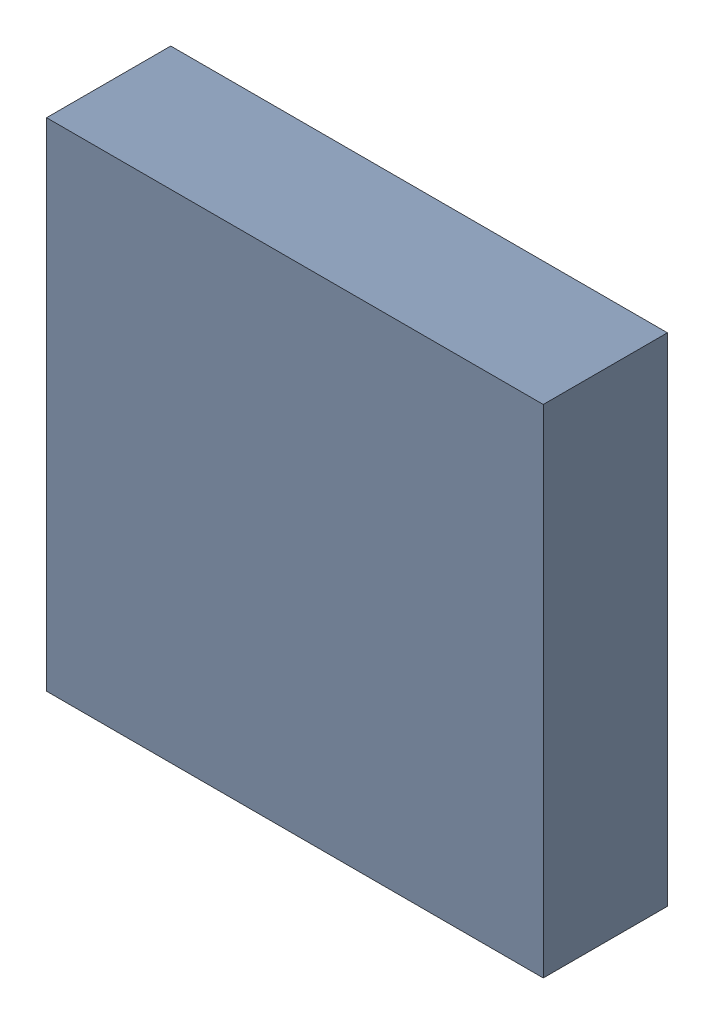
SolidWorks assembly U7, configuration Default. Lengths in mm.
Overall size (3 3 0.75).
2 component instances, 1 part files, 0 mates.
Components (placement in the parent):
- 836758256-1: 836758256 [Default] at (133.55 35.25 0) size (3 3 0.75)
  - Extruded_34-1: Extruded_34 [Default] at origin size (3 3 0.75)
